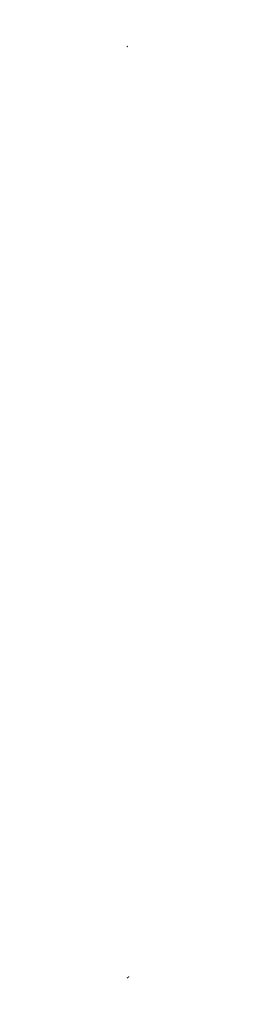
SolidWorks assembly Assem1, configuration Default. Lengths in mm.
Overall size (31 66926.09 173).
4 component instances, 4 part files, 6 mates.
Components (placement in the parent):
- PrismaticLinkOuter-1: PrismaticLinkOuter [Default] at (39.0462 51.578 76.2642) size (28 20 100)
- slidingBarPrismaticLink-1: slidingBarPrismaticLink [Default] at (39.0462 51.578 56.8412) x (0 1 0) z (-1 0 0) size (21.5 173 21.5)
- PrismaticLinkSlot-1: PrismaticLinkSlot [Default] at (29.0462 51.578 56.8412) x (0 -1 0) z (0 0 1) size (70 9 15)
- rotor 2-1: rotor 2 [Default] at (29.0462 66912.668 110.689) x (0 0 1) z (-1 0 0) size (60 60 8)
Mates (geometry in assembly coordinates):
- Coincident6: coincident anti-aligned: plane of PrismaticLinkOuter-1 through (34.0462 46.578 26.2642) normal (1 0 0); plane of slidingBarPrismaticLink-1 through (34.0462 46.578 -28.1588) normal (-1 0 0)
- Coincident7: coincident anti-aligned: plane of PrismaticLinkOuter-1 through (44.0462 56.578 26.2642) normal (0 -1 0); plane of slidingBarPrismaticLink-1 through (34.0462 56.578 -28.1588) normal (0 1 0)
- Coincident8: coincident anti-aligned: plane of slidingBarPrismaticLink-1 through (38.0462 51.578 56.8412) normal (-1 0 0); plane of PrismaticLinkSlot-1 through (38.0462 51.578 56.8412) normal (1 0 0)
- Coincident9: coincident anti-aligned: plane of slidingBarPrismaticLink-1 through (38.0462 46.578 64.3412) normal (0 0 -1); plane of PrismaticLinkSlot-1 through (34.0462 86.578 64.3412) normal (0 0 1)
- Coincident10: coincident aligned: plane of slidingBarPrismaticLink-1 through (34.0462 56.578 -28.1588) normal (0 1 0); plane of PrismaticLinkSlot-1 through (38.0462 56.578 64.3412) normal (0 1 0)
- Coincident11: coincident anti-aligned: plane of PrismaticLinkSlot-1 through (29.0462 51.578 56.8412) normal (-1 0 0); plane of rotor 2-1 through (29.0462 66912.668 110.689) normal (1 0 0)
